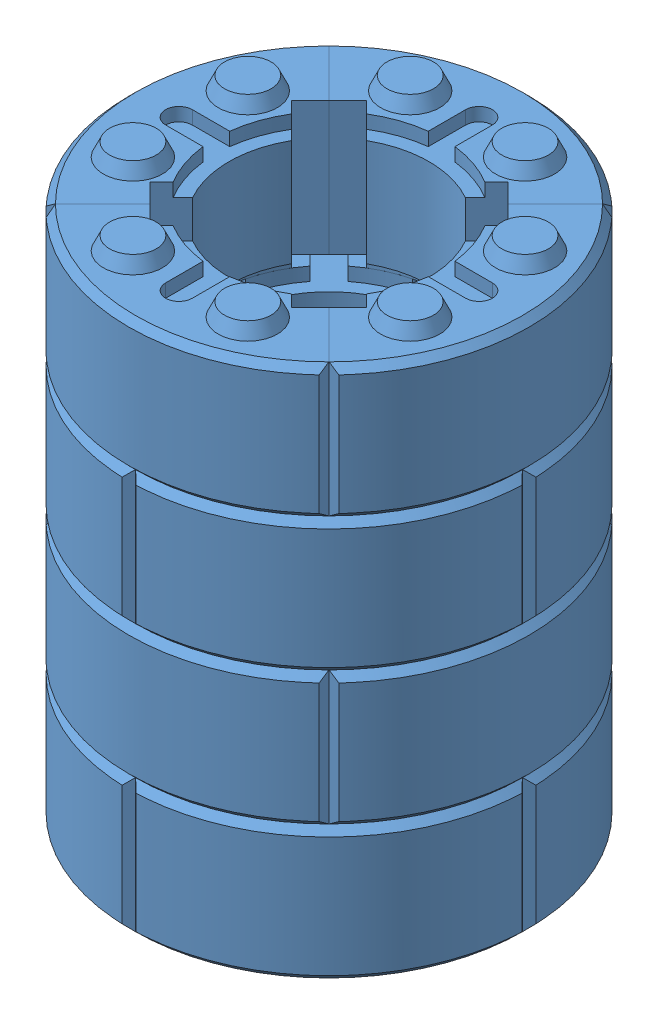
SolidWorks assembly Assem2, configuration Default. Lengths in mm.
Overall size (424.01 410 424.01).
20 component instances, 1 part files, 9 mates.
Components (placement in the parent):
- 300dia brick ass-1: 300dia brick ass [Default] at (104.851 16.1803 -101.7236) size (299.82 110 299.82)
  - pillar brick 300dia-1: pillar brick 300dia [Default] at (-142.4139 -67.4386 119.003) size (149.91 110 149.91)
  - pillar brick 300dia-2: pillar brick 300dia [Default] at (-142.4139 -67.4386 119.003) x (0 0 -1) z (1 0 0) size (149.91 110 149.91)
  - pillar brick 300dia-3: pillar brick 300dia [Default] at (-142.4139 -67.4386 119.003) x (-1 0 0) z (0 0 -1) size (149.91 110 149.91)
  - pillar brick 300dia-4: pillar brick 300dia [Default] at (-142.4139 -67.4386 119.003) x (0 0 1) z (-1 0 0) size (149.91 110 149.91)
- 300dia brick ass-2: 300dia brick ass [Default] at (147.2867 116.1803 33.8334) x (0.707107 0 0.707107) z (-0.707107 0 0.707107) size (299.82 110 299.82)
  - pillar brick 300dia-1: pillar brick 300dia [Default] at (-142.4139 -67.4386 119.003) size (149.91 110 149.91)
  - pillar brick 300dia-2: pillar brick 300dia [Default] at (-142.4139 -67.4386 119.003) x (0 0 -1) z (1 0 0) size (149.91 110 149.91)
  - pillar brick 300dia-3: pillar brick 300dia [Default] at (-142.4139 -67.4386 119.003) x (-1 0 0) z (0 0 -1) size (149.91 110 149.91)
  - pillar brick 300dia-4: pillar brick 300dia [Default] at (-142.4139 -67.4386 119.003) x (0 0 1) z (-1 0 0) size (149.91 110 149.91)
- 300dia brick ass-3: 300dia brick ass [Default] at (104.851 216.1803 -101.7236) size (299.82 110 299.82)
  - pillar brick 300dia-1: pillar brick 300dia [Default] at (-142.4139 -67.4386 119.003) size (149.91 110 149.91)
  - pillar brick 300dia-2: pillar brick 300dia [Default] at (-142.4139 -67.4386 119.003) x (0 0 -1) z (1 0 0) size (149.91 110 149.91)
  - pillar brick 300dia-3: pillar brick 300dia [Default] at (-142.4139 -67.4386 119.003) x (-1 0 0) z (0 0 -1) size (149.91 110 149.91)
  - pillar brick 300dia-4: pillar brick 300dia [Default] at (-142.4139 -67.4386 119.003) x (0 0 1) z (-1 0 0) size (149.91 110 149.91)
- 300dia brick ass-4: 300dia brick ass [Default] at (147.2867 316.1803 33.8334) x (0.707107 0 0.707107) z (-0.707107 0 0.707107) size (299.82 110 299.82)
  - pillar brick 300dia-1: pillar brick 300dia [Default] at (-142.4139 -67.4386 119.003) size (149.91 110 149.91)
  - pillar brick 300dia-2: pillar brick 300dia [Default] at (-142.4139 -67.4386 119.003) x (0 0 -1) z (1 0 0) size (149.91 110 149.91)
  - pillar brick 300dia-3: pillar brick 300dia [Default] at (-142.4139 -67.4386 119.003) x (-1 0 0) z (0 0 -1) size (149.91 110 149.91)
  - pillar brick 300dia-4: pillar brick 300dia [Default] at (-142.4139 -67.4386 119.003) x (0 0 1) z (-1 0 0) size (149.91 110 149.91)
Mates (geometry in assembly coordinates):
- Concentric1: concentric anti-aligned: circle of 300dia brick ass-1/pillar brick 300dia-3; circle of 300dia brick ass-2/pillar brick 300dia-4
- Concentric3: concentric anti-aligned: circle of 300dia brick ass-1/pillar brick 300dia-4; circle of 300dia brick ass-2/pillar brick 300dia-4
- Concentric4: concentric anti-aligned: circle of 300dia brick ass-1/pillar brick 300dia-4; circle of 300dia brick ass-2/pillar brick 300dia-1
- Coincident5: coincident anti-aligned: plane of 300dia brick ass-1/pillar brick 300dia-4 through (-37.5629 48.7417 17.2794) normal (0 1 0); plane of 300dia brick ass-2/pillar brick 300dia-1 through (-37.5629 48.7417 17.2794) normal (0 -1 0)
- Concentric5: concentric anti-aligned: circle of 300dia brick ass-2/pillar brick 300dia-1; circle of 300dia brick ass-3/pillar brick 300dia-1
- Coincident6: coincident anti-aligned: plane of 300dia brick ass-2/pillar brick 300dia-1 through (-37.5629 148.7417 17.2794) normal (0 1 0); plane of 300dia brick ass-3/pillar brick 300dia-1 through (-37.5629 148.7417 17.2794) normal (0 -1 0)
- Concentric7: concentric: circle of 300dia brick ass-3/pillar brick 300dia-1; circle of 300dia brick ass-4/pillar brick 300dia-2
- Concentric8: concentric: circle of 300dia brick ass-3/pillar brick 300dia-1; circle of 300dia brick ass-4/pillar brick 300dia-1
- Coincident8: coincident anti-aligned: plane of 300dia brick ass-3/pillar brick 300dia-4 through (-37.5629 248.7417 17.2794) normal (0 1 0); plane of 300dia brick ass-4/pillar brick 300dia-4 through (-37.5629 248.7417 17.2794) normal (0 -1 0)
